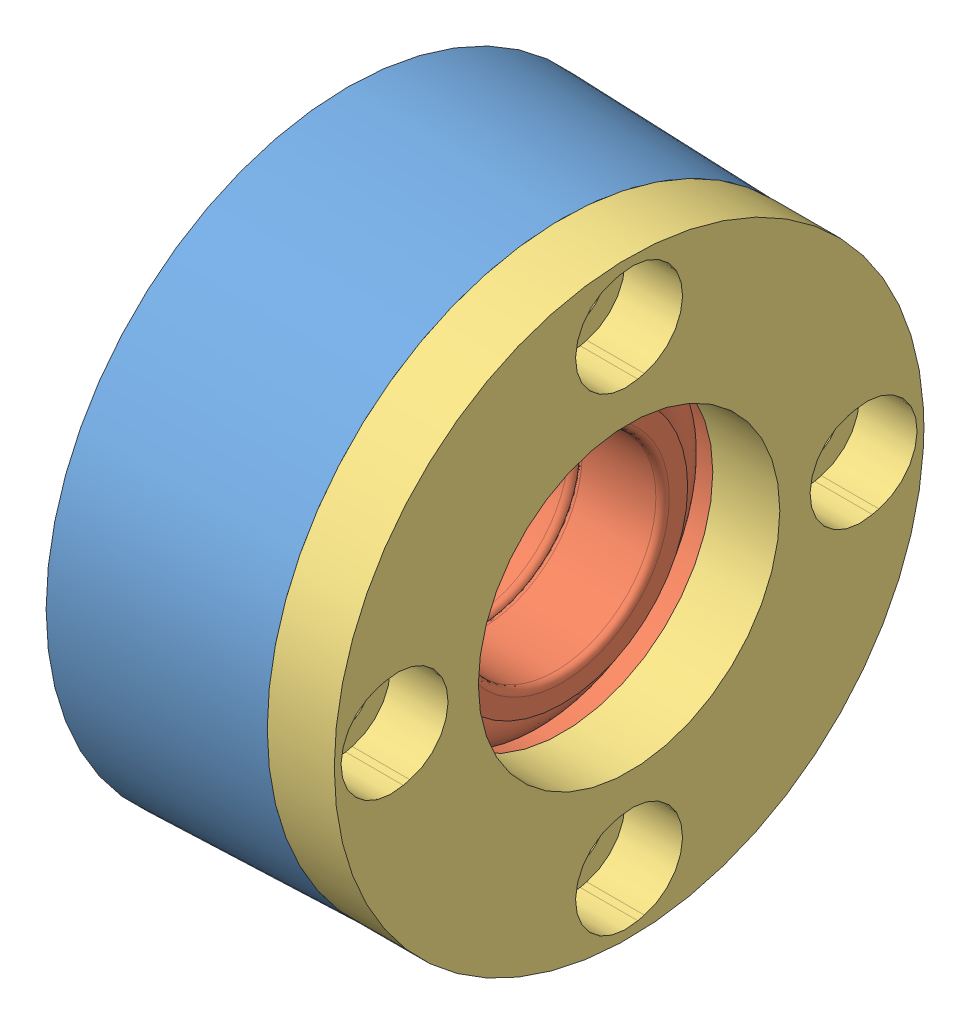
SolidWorks assembly KR.10.04, configuration Default. Lengths in mm.
Overall size (47 90 90).
4 component instances, 3 part files, 6 mates.
Components (placement in the parent):
- KR.13.04-1: KR.13.04 [Default] at (12.6419 59.8002 55.0628) size (37 90 90)
- radial ball bearing_68_din-1: radial ball bearing_68_din [DIN 625-6006] at (43.1419 59.8002 55.0628) x (1 0 0) z (0 0.004488 0.99999) size (13 55 55)
- radial ball bearing_68_din-2: radial ball bearing_68_din [DIN 625-6006] at (30.1419 59.8002 55.0628) x (1 0 0) z (0 -0.03979 0.999208) size (13 55 55)
- KR.13.05-1: KR.13.05 [Default] at (49.6419 59.8002 55.0628) x (0 0 -1) z (1 0 0) size (88 88 10)
Mates (geometry in assembly coordinates):
- Eş Merkezli1: concentric anti-aligned: cylinder of KR.13.04-1 through (12.6419 59.8002 55.0628) axis (-1 0 0) radius 27.5; cylinder of radial ball bearing_68_din-2 through (9.5044 59.8002 55.0628) axis (1 0 0) radius 27.5
- Çakışık1: coincident anti-aligned: plane of KR.13.04-1 through (23.6419 80.8002 55.0628) normal (1 0 0); plane of radial ball bearing_68_din-2 through (23.6419 83.5314 56.0078) normal (-1 0 0)
- Eş Merkezli2: concentric anti-aligned: cylinder of KR.13.04-1 through (12.6419 59.8002 55.0628) axis (-1 0 0) radius 27.5; cylinder of radial ball bearing_68_din-1 through (22.5044 59.8002 55.0628) axis (1 0 0) radius 27.5
- Çakışık2: coincident anti-aligned: plane of radial ball bearing_68_din-1 through (36.6419 83.5499 54.9562) normal (-1 0 0); plane of radial ball bearing_68_din-2 through (36.6419 86.2792 56.1172) normal (1 0 0)
- Çakışık3: coincident anti-aligned: plane of KR.13.04-1 through (49.6419 103.8002 55.0628) normal (1 0 0); plane of KR.13.05-1 through (49.6419 59.8002 55.0628) normal (-1 0 0)
- Eş Merkezli3: concentric anti-aligned: cone of KR.13.04-1 through (49.6419 59.8002 55.0628) axis (1 0 0); cylinder of KR.13.05-1 through (59.6419 59.8002 55.0628) axis (-1 0 0) radius 44
